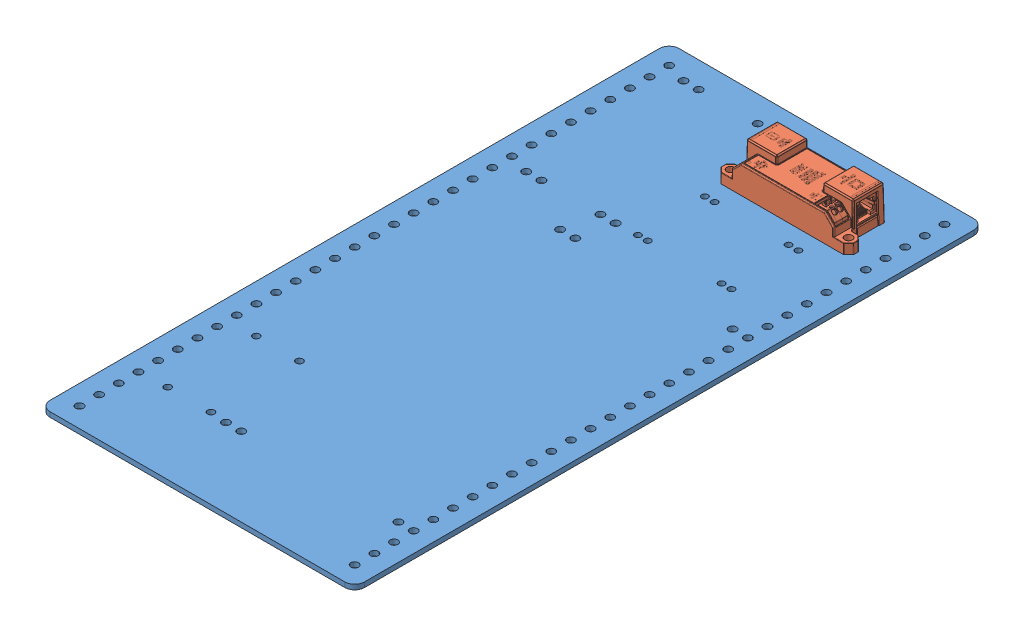
SolidWorks assembly Electrical Layout V2, configuration Default. Lengths in mm.
Overall size (203.2 25.43 406.4).
8 component instances, 7 part files, 3 mates.
Components (placement in the parent):
- Electrical Board V2-1: Electrical Board V2 [Default] at (117.607 185.839 239.5462) size (203.2 3.17 406.4)
- REV PDH-1: REV PDH [Default] at (135.1438 211.292 235.9642) size (112.73 39.72 227.13) (hidden)
- Robot Radio OM5P-AN-1: Robot Radio OM5P-AN [Default] at (41.2858 201.7477 138.6446) size (69.89 25.47 95.8) (hidden)
- REV Pnematics Hub-1: REV Pnematics Hub [Default] at (153.2274 198.3324 92.61) size (47.63 18.64 111.13) (hidden)
- REV Radio Power Module-1: REV Radio Power Module [Default] at (213.1305 200.1392 95.9014) size (85.73 22.25 31.75) (hidden)
- RoboRIO2-1: RoboRIO2 [Default] at (163.0972 198.666 -24.3437) x (1 0 0) z (0 1 0) size (146.28 143.18 34.81) (hidden)
- Voltage Regulator Module-1: Voltage Regulator Module [Default] at (41.523 206.1078 118.0127) size (56.39 19.92 51.56) (hidden)
- REV Radio Power Module-4: REV Radio Power Module [Default] at (168.5829 189.014 -2.1329) x (-1 0 0) z (0 0 -1) size (85.73 22.25 31.75)
Mates (geometry in assembly coordinates):
- Coincident1: coincident anti-aligned: plane of Electrical Board V2-1 through (39.7172 189.014 351.5872) normal (0 1 0); plane of RoboRIO2-1 through (163.0972 189.014 -24.3437) normal (0 -1 0)
- Coincident4: coincident anti-aligned: plane of Electrical Board V2-1 through (39.7172 189.014 351.5872) normal (0 1 0); plane of REV Radio Power Module-4 through (135.1579 189.014 -16.5079) normal (0 -1 0)
- Parallel3: parallel anti-aligned: line of REV Radio Power Module-4 through (202.5505 189.014 -18.0079) axis (-1 0 0)
